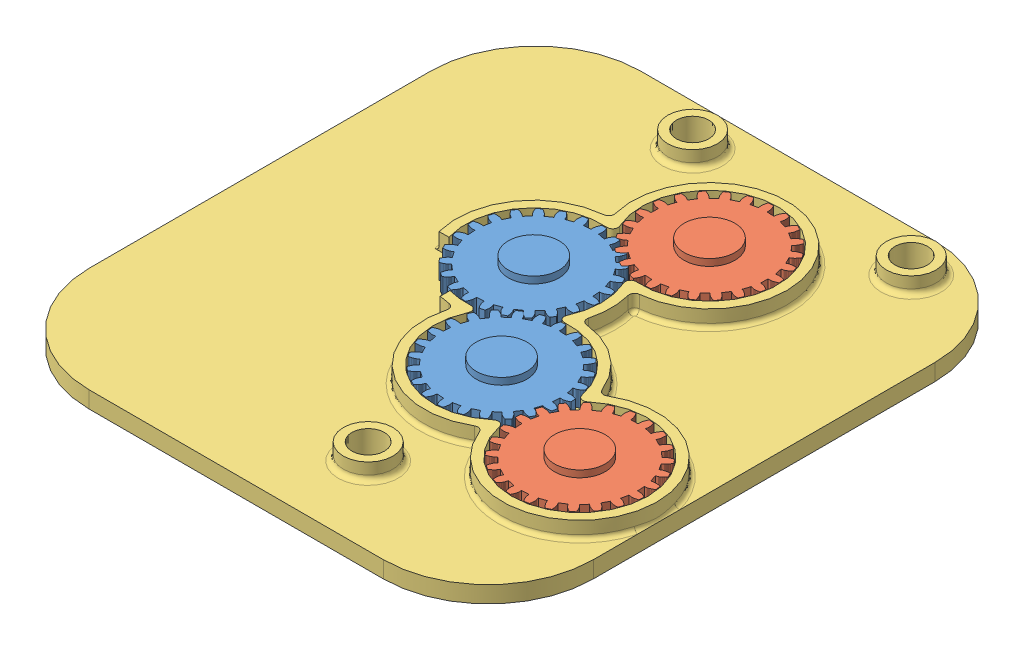
SolidWorks assembly wrist_block_test, configuration Default. Lengths in mm.
Overall size (96.01 12.03 105).
22 component instances, 8 part files, 27 mates.
Components (placement in the parent):
- w_t1_test-1: w_t1_test [Default] at (40.4355 52.1209 81.7577) size (96 12.88 105) (hidden)
- pulley_MX-28-6: pulley_MX-28 [Default] at (19.6355 93.8959 63.2077) x (-1 0 0) z (0 0 -1) size (38.36 58.4 42.92) (hidden)
  - dynamixel MX-28-exposed-1: dynamixel MX-28-exposed [Back Off] at origin size (35.6 50.6 39.77)
  - w_p1-1: w_p1 [Default] at (0 0 23.67) x (0.707107 -0.707107 0) z (0 0 1) size (26.25 28 6)
  - w_ac-1: w_ac [Default] at (12.375 12.125 -8.75) x (0 -1 0) z (0 0 -1) size (48.25 27.65 4)
- pulley_MX-28-5: pulley_MX-28 [Default] at (61.2355 93.8959 63.2077) x (-1 0 0) z (0 0 -1) size (38.36 58.4 42.92) (hidden)
  - dynamixel MX-28-exposed-1: dynamixel MX-28-exposed [Back Off] at origin size (35.6 50.6 39.77)
  - w_p1-1: w_p1 [Default] at (0 0 23.67) x (0.707107 -0.707107 0) z (0 0 1) size (26.25 28 6)
  - w_ac-1: w_ac [Default] at (12.375 12.125 -8.75) x (0 -1 0) z (0 0 -1) size (48.25 27.65 4)
- pulley_MX-28-4: pulley_MX-28 [Default] at (61.2355 93.8959 98.3077) size (38.36 58.4 42.92) (hidden)
  - dynamixel MX-28-exposed-1: dynamixel MX-28-exposed [Back Off] at origin size (35.6 50.6 39.77)
  - w_p1-1: w_p1 [Default] at (0 0 23.67) x (0.707107 -0.707107 0) z (0 0 1) size (26.25 28 6)
  - w_ac-1: w_ac [Default] at (12.375 12.125 -8.75) x (0 -1 0) z (0 0 -1) size (48.25 27.65 4)
- gear_MX-28-8: gear_MX-28 [Default] at (28.736 105.7506 133.1374) x (-1 0 0) z (0 -1 0) size (35.6 52.23 39.77) (hidden)
  - dynamixel MX-28-exposed-1: dynamixel MX-28-exposed [Back Off] at (8.6005 39.3797 35.4547) size (35.6 50.6 39.77)
  - w_g1-2: w_g1 [Default] at (8.6005 39.3797 55.9747) size (25.49 25.49 3)
  - w_ac-1: w_ac [Default] at (20.9755 51.5047 26.7047) x (0 -1 0) z (0 0 -1) size (48.25 27.65 4)
- w_g2-1: w_g2 [Default] at (37.1061 49.7759 76.7872) x (0.651238 0 -0.758874) z (0 -1 0) size (25.39 25.39 5.6)
- w_g2-2: w_g2 [Default] at (50.7355 49.7759 96.5416) x (0.998386 0 0.056786) z (0 -1 0) size (25.39 25.39 5.6)
- w_g3-1: w_g3 [Default] at (73.4306 49.7759 104.3477) x (0.979063 0 0.203556) z (0 -1 0) size (25.39 25.39 12.03)
- w_g3-2: w_g3 [Default] at (50.9355 49.7759 57.1722) x (-0.053218 0 0.998583) z (0 -1 0) size (25.39 25.39 12.03)
- w_t2-1: w_t2 [Default] at (40.4355 43.4209 81.7577) size (96 6.36 105)
Mates (geometry in assembly coordinates):
- Coincident1: coincident anti-aligned: plane of w_t1_test-1 through (40.4355 55.2959 81.7577) normal (0 1 0); plane of pulley_MX-28-6/dynamixel MX-28-exposed-1 through (32.3355 55.2959 50.2077) normal (0 -1 0)
- Coincident2: coincident anti-aligned: plane of w_t1_test-1 through (40.4355 60.7959 48.2077) normal (0 0 1); plane of pulley_MX-28-6/dynamixel MX-28-exposed-1 through (19.6355 93.8959 48.2077) normal (0 0 -1)
- Coincident3: coincident anti-aligned: plane of w_t1_test-1 through (37.4355 60.7959 81.7577) normal (-1 0 0); plane of pulley_MX-28-6/dynamixel MX-28-exposed-1 through (37.4355 99.8959 50.2077) normal (1 0 0)
- Coincident4: coincident anti-aligned: plane of w_t1_test-1 through (40.4355 55.2959 81.7577) normal (0 1 0); plane of pulley_MX-28-5/dynamixel MX-28-exposed-1 through (73.9355 55.2959 50.2077) normal (0 -1 0)
- Coincident5: coincident anti-aligned: plane of w_t1_test-1 through (43.4355 60.7959 81.7577) normal (1 0 0); plane of pulley_MX-28-5/dynamixel MX-28-exposed-1 through (43.4355 61.2959 50.2077) normal (-1 0 0)
- Coincident6: coincident anti-aligned: plane of w_t1_test-1 through (40.4355 60.7959 48.2077) normal (0 0 1); plane of pulley_MX-28-5/dynamixel MX-28-exposed-1 through (61.2355 93.8959 48.2077) normal (0 0 -1)
- Coincident12: coincident anti-aligned: plane of w_t1_test-1 through (40.4355 55.2959 81.7577) normal (0 1 0); plane of pulley_MX-28-4/dynamixel MX-28-exposed-1 through (48.5355 55.2959 111.3077) normal (0 -1 0)
- Coincident14: coincident anti-aligned: plane of w_t1_test-1 through (40.4355 60.7959 113.3077) normal (0 0 -1); plane of pulley_MX-28-4/dynamixel MX-28-exposed-1 through (61.2355 93.8959 113.3077) normal (0 0 1)
- Coincident15: coincident anti-aligned: plane of w_t1_test-1 through (43.4355 60.7959 81.7577) normal (1 0 0); plane of pulley_MX-28-4/dynamixel MX-28-exposed-1 through (43.4355 99.8959 111.3077) normal (-1 0 0)
- Coincident16: coincident anti-aligned: plane of w_t1_test-1 through (40.4355 55.2959 81.7577) normal (0 1 0); plane of gear_MX-28-8/dynamixel MX-28-exposed-1 through (20.1355 55.2959 93.7577) normal (0 -1 0)
- Concentric2: concentric anti-aligned: circle of w_t1_test-1; circle of gear_MX-28-8/dynamixel MX-28-exposed-1
- Concentric3: concentric anti-aligned: circle of w_t1_test-1; circle of gear_MX-28-8/dynamixel MX-28-exposed-1
- Coincident20: coincident aligned: plane of gear_MX-28-8/w_g1-2 through (20.1355 46.7759 93.7577) normal (0 -1 0); plane of w_g2-1 through (37.1061 46.7759 76.7872) normal (0 -1 0)
- Concentric4: concentric aligned: circle of w_g2-1; circle of w_t1_test-1
- Coincident21: coincident aligned: plane of w_g2-1 through (37.1061 46.7759 76.7872) normal (0 -1 0); plane of w_g2-2 through (50.7355 46.7759 96.5416) normal (0 -1 0)
- Concentric5: concentric aligned: circle of w_t1_test-1; circle of w_g2-2
- Coincident22: coincident aligned: plane of w_g2-2 through (50.7355 46.7759 96.5416) normal (0 -1 0); plane of w_g3-1 through (73.4306 46.7759 104.3477) normal (0 -1 0)
- Concentric6: concentric anti-aligned: circle of w_t1_test-1; circle of w_g3-1
- Coincident23: coincident aligned: plane of gear_MX-28-8/w_g1-2 through (20.1355 46.7759 93.7577) normal (0 -1 0); plane of w_g3-2 through (50.9355 46.7759 57.1722) normal (0 -1 0)
- Concentric7: concentric anti-aligned: circle of w_t1_test-1; circle of w_g3-2
- Coincident24: coincident aligned: plane of w_t1_test-1 through (-7.5645 55.2959 81.7577) normal (-1 0 0); plane of w_t2-1 through (-7.5645 46.5959 81.7577) normal (-1 0 0)
- Coincident25: coincident aligned: plane of w_t1_test-1 through (40.4355 55.2959 136.7577) normal (0 0 1); plane of w_t2-1 through (40.4355 46.5959 136.7577) normal (0 0 1)
- Coincident26: coincident anti-aligned: plane of w_t2-1 through (50.7355 45.4759 96.5416) normal (0 1 0); plane of w_g2-1 through (37.1061 45.4759 76.7872) normal (0 -1 0)
- Coincident27: coincident anti-aligned: plane of w_t2-1 through (40.4355 43.4209 81.7577) normal (0 -1 0); plane of ? through (40.7344 43.4209 106.3313) normal (0 1 0)
- Parallel1: parallel aligned: plane of w_t2-1 through (40.4355 46.5959 31.7577) normal (0 0 -1); plane of ? through (40.7344 37.2538 100.389) normal (0 0 -1)
- Coincident28: coincident anti-aligned: plane of w_t2-1 through (40.4355 43.4209 81.7577) normal (0 -1 0); plane of ? through (20.1199 43.4209 60.6318) normal (0 1 0)
- Parallel2: parallel aligned: plane of w_t2-1 through (-7.5645 46.5959 81.7577) normal (-1 0 0); plane of ? through (18.9199 39.7209 56.4318) normal (-1 0 0)
